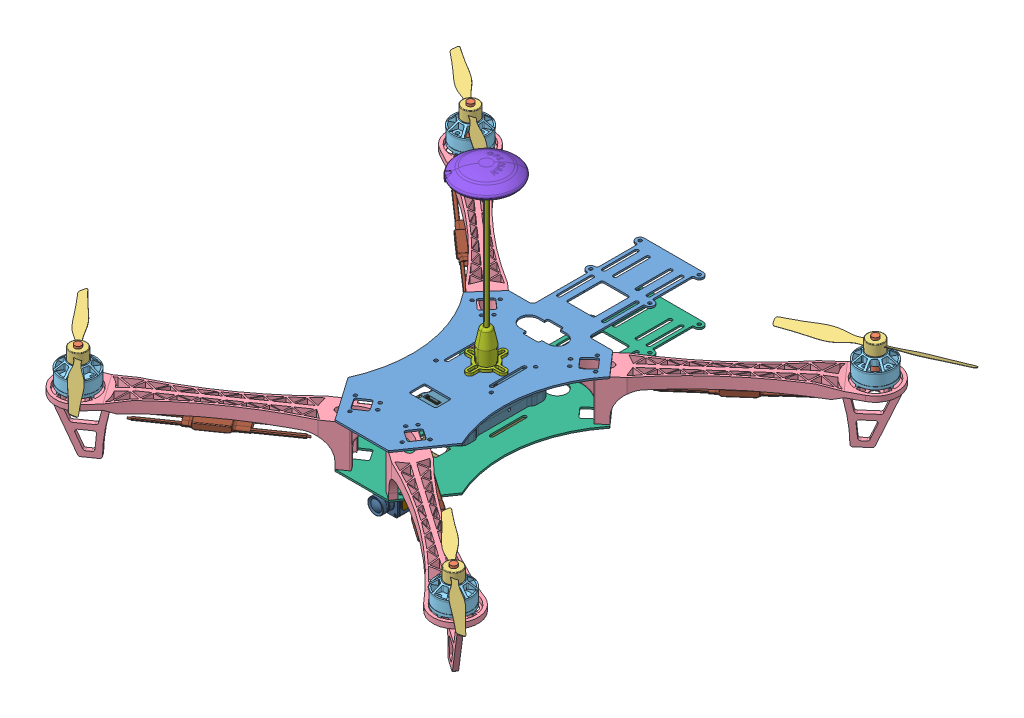
SolidWorks assembly Assem1, configuration Default. Lengths in mm.
Overall size (493.52 228.61 471.44).
54 component instances, 25 part files, 67 mates.
Components (placement in the parent):
- base-1: base [Default] at origin size (132.15 1.53 281.81)
- motor pin-1: motor pin [Default] at (-170.5066 0.8 186.2221) x (0.992347 0 0.123483) z (-0.123483 0 0.992347) size (6 30 6)
- peopulor-1: peopulor [Default] at (-170.5066 18.65 186.2221) x (0.674375 0 0.738389) z (-0.738389 0 0.674375) size (139.83 10 15)
- pram-1: pram [Default] at (44.8922 -12.7328 98.3012) x (0.81926 0 0.573422) z (-0.573422 0 0.81926) size (220 55.88 40.89)
- pram-2: pram [Default] at (-44.8922 -12.7328 98.3012) x (-0.81926 0 0.573422) z (-0.573422 0 -0.81926) size (220 55.88 40.89)
- pram-6: pram [Default] at (67.7631 -12.7328 -79.4744) x (0.751034 0 -0.660263) z (0.660263 0 0.751034) size (220 55.88 40.89)
- pram-7: pram [Default] at (-67.7631 -12.7328 -79.4744) x (-0.751034 0 -0.660263) z (0.660263 0 -0.751034) size (220 55.88 40.89)
- motor-3: motor [Default] at (182.9167 -0.85 -180.7104) x (0.751034 0 -0.660263) z (0.660263 0 0.751034) size (32 21.17 32)
- motor-4: motor [Default] at (170.8716 -0.85 188.2902) x (0.573422 0 -0.81926) z (0.81926 0 0.573422) size (32 21.17 32)
- motor-5: motor [Default] at (-170.5066 -0.85 186.2221) x (-0.81926 0 0.573422) z (-0.573422 0 -0.81926) size (32 21.17 32)
- motor-6: motor [Default] at (-182.9167 -0.85 -180.7104) x (-0.751034 0 -0.660263) z (0.660263 0 -0.751034) size (32 21.17 32)
- peopulor-3: peopulor [Default] at (-182.9167 18.65 -180.7104) x (0.801444 0 0.59807) z (-0.59807 0 0.801444) size (139.83 10 15)
- motor pin-3: motor pin [Default] at (-182.9167 0.8 -180.7104) x (0.997837 0 -0.065743) z (0.065743 0 0.997837) size (6 30 6)
- motor pin-4: motor pin [Default] at (170.8716 0.8 188.2902) x (0.967568 0 -0.252612) z (0.252612 0 0.967568) size (6 30 6)
- peopulor-4: peopulor [Default] at (170.8716 18.65 188.2902) x (0.752483 0 0.658612) z (-0.658612 0 0.752483) size (139.83 10 15)
- peopulor-5: peopulor [Default] at (182.9167 18.65 -180.7104) x (-0.91818 0 0.396163) z (-0.396163 0 -0.91818) size (139.83 10 15)
- motor pin-5: motor pin [Default] at (182.9167 0.8 -180.7104) x (0.902625 0 -0.430428) z (0.430428 0 0.902625) size (6 30 6)
- base 2-3: base 2 [Default] at (0 -38.84 0) size (132.15 1.53 281.81)
- GPS_MN8_ASM_STEP.STEP-1: GPS_MN8_ASM_STEP.STEP [Default] at (10.4219 65.1398 -11.916) size (75.84 157.4 75.99)
  - GPS MOD_L_ _SKELET_.STEP-1: GPS MOD_L_ _SKELET_.STEP [Default] at (-10.1619 -63.6098 0) size (36.5 144.9 36.5)
  - GPS M8N.STEP-1: GPS M8N.STEP [Default] at (-10.1619 81.2902 0) x (0.794386 0 0.607413) z (-0.607413 0 0.794386) size (53.76 12.5 54.56)
- camera gimbal assembly-1: camera gimbal assembly [Default] at (-11.8611 -38.59 66.4016) x (0.546944 0 0.837169) z (-0.837169 0 0.546944) size (48.97 31.09 42.31)
  - Camera gimball-1: Camera gimball [Default] at (0 -15.5 -15.5) x (-0.837169 0 -0.546944) z (0 -1 0) size (30 22.5 25.5)
  - camera DJI FPV-1: camera DJI FPV [Default] at (12.3482 -20.5 -7.4326) x (0.546944 0 -0.837169) z (0.837169 0 0.546944) size (20.5 21.17 32.8)
- 30A ESC-1: 30A ESC [Default] at (134.9042 -16.222 -126.4707) x (0.660263 0 0.751034) z (-0.751034 0 0.660263) size (28.83 9.95 119.13)
- 30A ESC-4: 30A ESC [Default] at (-75.741 -16.222 140.1047) x (0.573422 0 0.81926) z (-0.81926 0 0.573422) size (28.83 9.95 119.13)
- 30A ESC-5: 30A ESC [Default] at (83.6226 -16.222 105.1981) x (0.573422 0 -0.81926) z (0.81926 0 0.573422) size (28.83 9.95 119.13)
- 30A ESC-6: 30A ESC [Default] at (-115.926 -16.222 -133.8464) x (0.660263 0 -0.751034) z (0.751034 0 0.660263) size (28.83 9.95 119.13)
- PİL_3S-1: PİL_3S [Varsayılan] at (3.04 -50.4181 -22.076) size (42.49 23.16 88.44)
- Pixhawk.STEP-1: Pixhawk.STEP [Default] at (-5.9878 -37.31 -9.9262) x (1 0 0) z (0 1 0) size (62.89 81.3 15.33)
  - micro USB.STEP-1: micro USB.STEP [Default] at (-38.5288 4.0262 13.8589) x (0 1 0) z (-1 0 0) size (7.98 2.93 5.44)
  - Pixhawk APM.STEP-1: Pixhawk APM.STEP [Default] at (-25.3722 -39.1501 0) size (49.31 81.3 15.02)
  - DF13-3P-1.25DSA.STEP-1: DF13-3P-1.25DSA.STEP [Default] at (0.001 -60.127 12.2305) x (0 -1 0) z (-1 0 0) size (3.41 6.61 5.41)
  - DF13-5P-1.25DSA.STEP-1: DF13-5P-1.25DSA.STEP [Default] at (0.5502 -52.3839 12.2305) x (0 -1 0) z (-1 0 0) size (3.41 6.61 7.91)
  - DF13-6P-1.25DSA.STEP-1: DF13-6P-1.25DSA.STEP [Default] at (-27.5951 -60.0382 12.2305) x (0 -1 0) z (-1 0 0) size (3.41 6.61 9.16)
  - DF13-7P-1.25DSA.STEP-1: DF13-7P-1.25DSA.STEP [Default] at (-26.4213 -52.4032 12.2305) x (0 -1 0) z (-1 0 0) size (3.41 6.61 10.41)
  - DF13-4P-1.25DSA.STEP-1: DF13-4P-1.25DSA.STEP [Default] at (-0.0265 -37.0823 12.2305) x (0 -1 0) z (-1 0 0) size (3.41 6.61 6.66)
  - DF13-4P-1.25DSA.STEP-2: DF13-4P-1.25DSA.STEP [Default] at (-30.3382 -37.0823 12.2305) x (0 -1 0) z (-1 0 0) size (3.41 6.61 6.66)
  - DF13-5P-1.25DSA.STEP-2: DF13-5P-1.25DSA.STEP [Default] at (-14.4216 -37.0823 12.2305) x (0 -1 0) z (-1 0 0) size (3.41 6.61 7.91)
  - DF13-6P-1.25DSA.STEP-2: DF13-6P-1.25DSA.STEP [Default] at (-0.012 -29.2904 12.2305) x (0 -1 0) z (-1 0 0) size (3.41 6.61 9.16)
  - DF13-6P-1.25DSA.STEP-3: DF13-6P-1.25DSA.STEP [Default] at (-0.012 -21.2194 12.2305) x (0 -1 0) z (-1 0 0) size (3.41 6.61 9.16)
  - DF13-6P-1.25DSA.STEP-4: DF13-6P-1.25DSA.STEP [Default] at (-27.948 -29.2904 12.2305) x (0 -1 0) z (-1 0 0) size (3.41 6.61 9.16)
  - DF13-6P-1.25DSA.STEP-5: DF13-6P-1.25DSA.STEP [Default] at (-27.948 -21.2194 12.2305) x (0 -1 0) z (-1 0 0) size (3.41 6.61 9.16)
  - DF13-3P-1.25DSA.STEP-2: DF13-3P-1.25DSA.STEP [Default] at (-15.6441 -21.2194 12.2305) x (0 -1 0) z (-1 0 0) size (3.41 6.61 5.41)
  - DF13-2P-1.25DSA.STEP-1: DF13-2P-1.25DSA.STEP [Default] at (-11.2684 -12.1811 12.2305) x (0 -1 0) z (-1 0 0) size (3.41 6.61 4.16)
  - DF13-3P-1.25DSA.STEP-3: DF13-3P-1.25DSA.STEP [Default] at (-20.7011 -12.1811 12.2305) x (0 -1 0) z (-1 0 0) size (3.41 6.61 5.41)
  - pan head cross recess screw_iso_ISO 7045 - M1.6 x 3 - Z --- 3N.STEP-1: pan head cross recess screw_iso_ISO 7045 - M1.6 x 3 - Z --- 3N.STEP [Default] at (21.4278 32.5499 14.8) x (0 0 -1) z (1 0 0) size (4.27 3.2 3.2)
  - pan head cross recess screw_iso_ISO 7045 - M1.6 x 3 - Z --- 3N.STEP-2: pan head cross recess screw_iso_ISO 7045 - M1.6 x 3 - Z --- 3N.STEP [Default] at (-22.8722 32.5499 14.8) x (0 0 -1) z (1 0 0) size (4.27 3.2 3.2)
  - pan head cross recess screw_iso_ISO 7045 - M1.6 x 3 - Z --- 3N.STEP-3: pan head cross recess screw_iso_ISO 7045 - M1.6 x 3 - Z --- 3N.STEP [Default] at (21.4278 -29.5501 14.8) x (0 0 -1) z (1 0 0) size (4.27 3.2 3.2)
  - pan head cross recess screw_iso_ISO 7045 - M1.6 x 3 - Z --- 3N.STEP-4: pan head cross recess screw_iso_ISO 7045 - M1.6 x 3 - Z --- 3N.STEP [Default] at (-22.8722 -29.5501 14.8) x (0 0 -1) z (1 0 0) size (4.27 3.2 3.2)
  - Pi_ce10^Pixhawk.STEP-1: Pi_ce10^Pixhawk.STEP [Default] at (-25.3722 -39.1501 14.5) size (8.5 8.5 0.5)
  - Pi_ce11^Pixhawk.STEP-1: Pi_ce11^Pixhawk.STEP [Default] at (-25.3722 -39.1501 14.5) size (5.12 11.31 0.5)
  - Pi_ce12^Pixhawk.STEP-1: Pi_ce12^Pixhawk.STEP [Default] at (-25.3722 -37.5551 19.1403) x (1 0 0) z (0 0.083045 0.996546) size (2.5 9.53 0.5)
  - Pi_ce13^Pixhawk.STEP-1: Pi_ce13^Pixhawk.STEP [Default] at (-25.3722 -37.5551 19.1403) x (1 0 0) z (0 0.083045 0.996546) size (2.5 6.02 0.5)
Mates (geometry in assembly coordinates):
- Coincident2: coincident anti-aligned: plane of base-1 through (0 0 0) normal (0 -1 0); plane of pram-1 through (44.8922 0 98.3012) normal (0 1 0)
- Parallel1: parallel aligned: line of base-1 through (51.475 0 61.3813) axis (-0.573422 0 0.81926); line of pram-1 through (10.1081 0 69.0724) axis (-0.573422 0 0.81926)
- Coincident5: coincident anti-aligned: line of base-1 through (-51.475 0 61.3813) axis (0.573422 0 0.81926); plane of pram-2 through (-44.8922 0 98.3012) normal (0 1 0)
- Parallel2: parallel anti-aligned: line of base-1 through (-51.475 1.53 61.3813) axis (0.573422 0 0.81926); line of pram-2 through (-5.5207 0 75.6265) axis (-0.573422 0 -0.81926)
- Parallel3: parallel aligned: line of base-1 through (47 0 -79.196) axis (0.660263 0 0.751034); line of pram-6 through (31.132 0 -52.5967) axis (0.660263 0 0.751034)
- Coincident6: coincident anti-aligned: circle of base-1; plane of pram-6 through (67.7631 0 -79.4744) normal (0 1 0)
- Parallel4: parallel anti-aligned: line of base-1 through (-47 0 -79.196) axis (-0.660263 0 0.751034); line of pram-7 through (-36.4141 0 -46.5884) axis (0.660263 0 -0.751034)
- Coincident7: coincident anti-aligned: line of base-1 through (-47 0 -79.196) axis (1 0 0); plane of pram-7 through (-67.7631 0 -79.4744) normal (0 1 0)
- Coincident14: coincident aligned: line of pram-6 through (197.2319 -2.5 -180.8418) axis (0.997938 0 0.064185); line of motor-3 through (196.5763 -2.5 -180.884) axis (0.997938 0 0.064185)
- Coincident15: coincident aligned: line of pram-6 through (183.0546 -2.5 -166.495) axis (-0.064185 0 0.997938); line of motor-3 through (183.0903 -2.5 -167.0508) axis (-0.064185 0 0.997938)
- Coincident16: coincident anti-aligned: line of pram-1 through (187.9437 -2.5 184.2103) axis (-0.984775 0 0.173833); line of motor-4 through (184.102 -2.5 184.8885) axis (0.984775 0 -0.173833)
- Coincident17: coincident anti-aligned: point of pram-1; line of motor-4 through (174.2733 -2.5 201.5205) axis (0.173833 0 0.984775)
- Coincident18: coincident aligned: line of pram-2 through (-184.749 -2.5 184.7743) axis (-0.984775 0 -0.173833); line of motor-5 through (-184.102 -2.5 184.8885) axis (-0.984775 0 -0.173833)
- Coincident19: coincident aligned: line of pram-2 through (-174.5864 -2.5 203.2942) axis (0.173833 0 -0.984775); line of motor-5 through (-169.1729 -2.5 172.6267) axis (0.173833 0 -0.984775)
- Coincident20: coincident aligned: line of pram-7 through (-184.8809 -2.5 -194.8908) axis (-0.064185 0 -0.997938); line of motor-6 through (-184.8387 -2.5 -194.2352) axis (-0.064185 0 -0.997938)
- Coincident21: coincident aligned: line of pram-7 through (-200.4694 -2.5 -180.6336) axis (0.997938 0 -0.064185); line of motor-6 through (-169.3919 -2.5 -182.6324) axis (0.997938 0 -0.064185)
- Concentric23: concentric anti-aligned: cylinder of motor pin-1 through (-170.5066 30.8 186.2221) axis (0 -1 0) radius 3; cylinder of motor-5 through (-170.5066 -2.518 186.2221) axis (0 1 0) radius 3
- Coincident22: coincident anti-aligned: plane of motor pin-1 through (-170.5066 0.8 186.2221) normal (0 -1 0); plane of motor-5 through (-170.5066 0.8 186.2221) normal (0 1 0)
- Concentric24: concentric anti-aligned: cylinder of motor pin-1 through (-170.5066 30.8 186.2221) axis (0 -1 0) radius 3; cylinder of peopulor-1 through (-170.5066 18.65 186.2221) axis (0 1 0) radius 3
- Coincident23: coincident anti-aligned: plane of peopulor-1 through (-170.5066 18.65 186.2221) normal (0 -1 0); plane of motor-5 through (-170.5066 18.65 186.2221) normal (0 1 0)
- Concentric27: concentric anti-aligned: cylinder of peopulor-3 through (-182.9167 18.65 -180.7104) axis (0 1 0) radius 3; cylinder of motor pin-3 through (-182.9167 30.8 -180.7104) axis (0 -1 0) radius 3
- Concentric28: concentric anti-aligned: cylinder of motor-6 through (-182.9167 -2.518 -180.7104) axis (0 1 0) radius 3; cylinder of motor pin-3 through (-182.9167 30.8 -180.7104) axis (0 -1 0) radius 3
- Coincident27: coincident anti-aligned: plane of motor-6 through (-182.9167 0.8 -180.7104) normal (0 1 0); plane of motor pin-3 through (-182.9167 0.8 -180.7104) normal (0 -1 0)
- Coincident28: coincident anti-aligned: plane of motor-6 through (-182.9167 18.65 -180.7104) normal (0 1 0); plane of peopulor-3 through (-182.9167 18.65 -180.7104) normal (0 -1 0)
- Concentric29: concentric anti-aligned: cylinder of motor pin-4 through (170.8716 30.8 188.2902) axis (0 -1 0) radius 3; cylinder of peopulor-4 through (170.8716 18.65 188.2902) axis (0 1 0) radius 3
- Concentric30: concentric anti-aligned: cylinder of motor-4 through (170.8716 -2.518 188.2902) axis (0 1 0) radius 3; cylinder of motor pin-4 through (170.8716 30.8 188.2902) axis (0 -1 0) radius 3
- Coincident29: coincident anti-aligned: plane of motor-4 through (170.8716 0.8 188.2902) normal (0 1 0); plane of motor pin-4 through (170.8716 0.8 188.2902) normal (0 -1 0)
- Coincident30: coincident anti-aligned: plane of motor-4 through (170.8716 18.65 188.2902) normal (0 1 0); plane of peopulor-4 through (170.8716 18.65 188.2902) normal (0 -1 0)
- Concentric31: concentric anti-aligned: cylinder of peopulor-5 through (182.9167 18.65 -180.7104) axis (0 1 0) radius 3; cylinder of motor pin-5 through (182.9167 30.8 -180.7104) axis (0 -1 0) radius 3
- Concentric32: concentric anti-aligned: cylinder of motor-3 through (182.9167 -2.518 -180.7104) axis (0 1 0) radius 3; cylinder of motor pin-5 through (182.9167 30.8 -180.7104) axis (0 -1 0) radius 3
- Coincident31: coincident anti-aligned: plane of motor-3 through (182.9167 0.8 -180.7104) normal (0 1 0); plane of motor pin-5 through (182.9167 0.8 -180.7104) normal (0 -1 0)
- Coincident32: coincident anti-aligned: plane of motor-3 through (182.9167 18.65 -180.7104) normal (0 1 0); plane of peopulor-5 through (182.9167 18.65 -180.7104) normal (0 -1 0)
- Coincident36: coincident anti-aligned: plane of pram-6 through (69.4126 -37.31 -53.7022) normal (0 -1 0); plane of base 2-3 through (0 -37.31 0) normal (0 1 0)
- Coincident37: coincident aligned: cylinder of base-1 through (155.1713 1.53 13.7801) axis (0 -1 0) radius 114.1; circle of base 2-3
- Coincident38: coincident aligned: plane of base-1 through (65.7822 1.53 -57.8317) normal (0.751034 0 -0.660263); plane of base 2-3 through (65.7822 -37.31 -57.8317) normal (0.751034 0 -0.660263)
- Coincident39: coincident aligned: plane of base-1 through (1.68 1.53 0) normal (-1 0 0); plane of GPS_MN8_ASM_STEP.STEP-1/GPS MOD_L_ _SKELET_.STEP-1 through (1.68 3.93 -26.916) normal (-1 0 0)
- Coincident40: coincident anti-aligned: plane of base-1 through (0 1.53 0) normal (0 1 0); plane of GPS_MN8_ASM_STEP.STEP-1/GPS MOD_L_ _SKELET_.STEP-1 through (-14.74 1.53 -11.916) normal (0 -1 0)
- Coincident41: coincident aligned: line of base-1 through (1.68 1.53 3.084) axis (0 -1 0); line of GPS_MN8_ASM_STEP.STEP-1/GPS MOD_L_ _SKELET_.STEP-1 through (1.68 3.93 3.084) axis (0 -1 0)
- Coincident42: coincident anti-aligned: line of base 2-3 through (10.615 -38.84 45.924) axis (-1 0 0); line of camera gimbal assembly-1/Camera gimball-1 through (-8.385 -38.84 45.924) axis (1 0 0)
- Parallel5: parallel anti-aligned: plane of base 2-3 through (0 -38.84 0) normal (0 -1 0); plane of camera gimbal assembly-1/Camera gimball-1 through (1.115 -38.59 57.924) normal (0 1 0)
- Coincident44: coincident aligned: line of base 2-3 through (10.615 -37.31 45.924) axis (0 -1 0); line of camera gimbal assembly-1/Camera gimball-1 through (10.615 -38.84 45.924) axis (0 -1 0)
- Coincident45: coincident anti-aligned: plane of pram-6 through (211.8238 -10.38 -178.9013) normal (0 -1 0); plane of 30A ESC-1 through (134.9042 -10.38 -126.4707) normal (0 1 0)
- Tangent1: tangent anti-aligned: cylinder of pram-6 through (357.8361 -40.89 164.1299) axis (0 1 0) radius 366.24; plane of 30A ESC-1 through (142.2424 -10.38 -133.9808) normal (0.660263 0 0.751034)
- Coincident50: coincident: point of pram-6; plane of 30A ESC-1 through (92.6291 -10.38 -122.3238) normal (-0.751034 0 0.660263)
- Coincident52: coincident anti-aligned: line of pram-6 through (64.8271 -37.31 -58.9181) axis (-0.660263 0 -0.751034); line of base 2-3 through (47 -37.31 -79.196) axis (0.660263 0 0.751034)
- Coincident53: coincident anti-aligned: line of pram-6 through (47 -37.31 -79.196) axis (0 1 0); line of base 2-3 through (47 -37.31 -79.196) axis (0 -1 0)
- Coincident56: coincident aligned: line of pram-2 through (-27.6655 -37.31 95.3984) axis (0.573422 0 0.81926); line of base 2-3 through (-51.475 -37.31 61.3813) axis (0.573422 0 0.81926)
- Coincident57: coincident anti-aligned: line of pram-2 through (-24.225 -37.31 100.314) axis (0 1 0); line of base 2-3 through (-24.225 -37.31 100.314) axis (0 -1 0)
- Coincident58: coincident anti-aligned: line of pram-1 through (24.225 -37.31 100.314) axis (0.573422 0 -0.81926); line of base 2-3 through (51.475 -37.31 61.3813) axis (-0.573422 0 0.81926)
- Coincident59: coincident anti-aligned: line of pram-1 through (24.225 -37.31 100.314) axis (0 1 0); line of base 2-3 through (24.225 -37.31 100.314) axis (0 -1 0)
- Coincident60: coincident aligned: line of pram-7 through (-47 -37.31 -79.196) axis (-0.660263 0 0.751034); line of base 2-3 through (-47 -37.31 -79.196) axis (-0.660263 0 0.751034)
- Coincident61: coincident anti-aligned: line of pram-7 through (-47 -37.31 -79.196) axis (0 1 0); line of base 2-3 through (-47 -37.31 -79.196) axis (0 -1 0)
- Coincident63: coincident anti-aligned: plane of pram-2 through (-199.0379 -10.38 181.2365) normal (0 -1 0); plane of 30A ESC-4 through (-75.741 -10.38 140.1047) normal (0 1 0)
- Parallel8: parallel: line of pram-2 through (-140.8427 -10.38 181.0477) axis (0.573422 0 0.81926); plane of 30A ESC-4 through (-118.2156 -10.38 139.5647) normal (-0.81926 0 0.573422)
- Tangent4: tangent anti-aligned: cylinder of pram-2 through (-306.3348 -40.89 -175.8032) axis (0 1 0) radius 366.24; plane of 30A ESC-4 through (-81.3833 -10.38 113.7848) normal (-0.573422 0 -0.81926)
- Coincident67: coincident anti-aligned: plane of pram-1 through (175.5906 -10.38 214.7361) normal (0 -1 0); plane of 30A ESC-5 through (83.6226 -10.38 105.1981) normal (0 1 0)
- Parallel9: parallel: line of pram-1 through (147.0189 -10.38 172.2237) axis (0.573422 0 -0.81926); plane of 30A ESC-5 through (97.6574 -10.38 145.2906) normal (0.81926 0 0.573422)
- Tangent5: tangent anti-aligned: cylinder of pram-1 through (-123.1353 -40.89 437.7893) axis (0 1 0) radius 366.24; plane of 30A ESC-5 through (60.8251 -10.38 119.5106) normal (-0.573422 0 0.81926)
- Coincident69: coincident anti-aligned: plane of pram-7 through (-184.8256 -10.38 -209.6111) normal (0 -1 0); plane of 30A ESC-6 through (-115.926 -10.38 -133.8464) normal (0 1 0)
- Parallel10: parallel: line of pram-7 through (-161.1158 -10.38 -164.2074) axis (-0.660263 0 0.751034); plane of 30A ESC-6 through (-140.1627 -10.38 -122.135) normal (-0.751034 0 -0.660263)
- Tangent6: tangent anti-aligned: cylinder of pram-7 through (136.6742 -40.89 -398.3645) axis (0 1 0) radius 366.24; plane of 30A ESC-6 through (-124.3144 -10.38 -140.1621) normal (0.660263 0 -0.751034)
- Coincident71: coincident aligned: plane of base 2-3 through (18.54 -37.31 0) normal (1 0 0); plane of PİL_3S-1 through (18.54 -38.84 -52.076) normal (1 0 0)
- Coincident72: coincident anti-aligned: plane of base 2-3 through (0 -38.84 0) normal (0 -1 0); plane of PİL_3S-1 through (3.04 -38.84 -22.076) normal (0 1 0)
- Coincident73: coincident aligned: line of base 2-3 through (5.695 -38.84 -52.076) axis (-1 0 0); line of PİL_3S-1 through (15.54 -38.84 -52.076) axis (-1 0 0)
- Coincident74: coincident anti-aligned: plane of base 2-3 through (0 -37.31 0) normal (0 1 0); plane of Pixhawk.STEP-1/Pixhawk APM.STEP-1 through (-31.36 -37.31 29.224) normal (0 -1 0)
- Coincident75: coincident aligned: plane of PİL_3S-1 through (-12.46 -38.84 -52.076) normal (0 0 -1); plane of Pixhawk.STEP-1/Pixhawk APM.STEP-1 through (-31.36 -22.31 -52.076) normal (0 0 -1)
- Coincident76: coincident: line of PİL_3S-1 through (15.54 -38.84 7.924) axis (0 0 -1); plane of Pixhawk.STEP-1/Pixhawk APM.STEP-1 through (15.54 -22.31 -35.076) normal (1 0 0)
